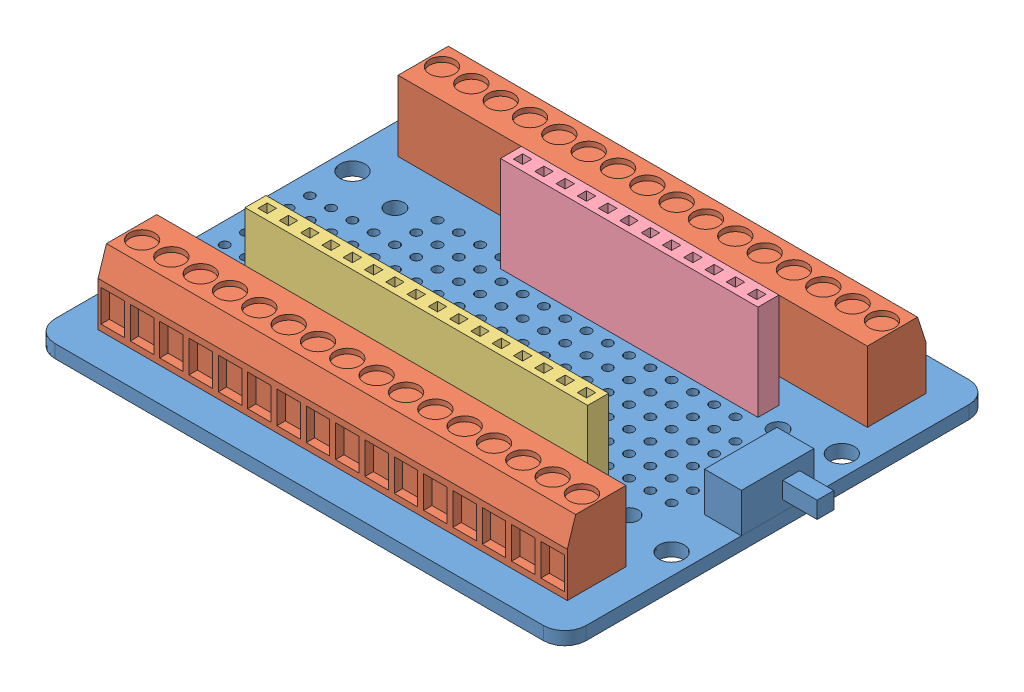
SolidWorks assembly 2926 Terminal Block Breakout FeatherWing, configuration Default. Lengths in mm.
Overall size (67.5 15.2 50.8).
5 component instances, 4 part files, 9 mates.
Components (placement in the parent):
- 2926 Terminal Block Breakout FeatherWing-1: 2926 Terminal Block Breakout FeatherWing [Default] at origin size (67.5 6.27 50.8)
- screw_terminal_16x_3.5pitch-1: screw_terminal_16x_3.5pitch [Default] at (-28 1.57 14.4) x (0 0 1) z (-1 0 0) size (7 12.2 56)
- screw_terminal_16x_3.5pitch-2: screw_terminal_16x_3.5pitch [Default] at (28 1.57 -14.4) x (0 0 -1) z (1 0 0) size (7 12.2 56)
- header_f16_tall-1: header_f16_tall [Default] at (-20.445 1.57 10.16) size (40.89 14.4 2.5)
- header_f12_tall-1: header_f12_tall [Default] at (-10.285 1.57 -10.16) size (30.73 14.4 2.5)
Mates (geometry in assembly coordinates):
- Coincident1: coincident anti-aligned: plane of 2926 Terminal Block Breakout FeatherWing-1 through (0 1.57 0) normal (0 1 0); plane of screw_terminal_16x_3.5pitch-1 through (28 1.57 21.4) normal (0 -1 0)
- Distance1: distance = 11 mm anti-aligned: plane of screw_terminal_16x_3.5pitch-1 through (28 1.57 14.4) normal (0 0 -1); plane of 2926 Terminal Block Breakout FeatherWing-1 through (-31.7 1.57 25.4) normal (0 0 1)
- Coincident3: coincident anti-aligned: plane of screw_terminal_16x_3.5pitch-1 through (0 1.57 14.4) normal (-1 0 0)
- Concentric1: concentric aligned: cylinder of 2926 Terminal Block Breakout FeatherWing-1 through (-19.05 1.57 10.16) axis (0 -1 0) radius 0.55; line of header_f16_tall-1 through (-19.05 1.57 10.16) axis (0 -1 0)
- Concentric2: concentric aligned: cylinder of 2926 Terminal Block Breakout FeatherWing-1 through (19.05 1.57 10.16) axis (0 -1 0) radius 0.55; line of header_f16_tall-1 through (19.05 1.57 10.16) axis (0 -1 0)
- Coincident4: coincident anti-aligned: plane of 2926 Terminal Block Breakout FeatherWing-1 through (0 1.57 0) normal (0 1 0); plane of header_f16_tall-1 through (-20.445 1.57 11.41) normal (0 -1 0)
- Concentric3: concentric aligned: cylinder of 2926 Terminal Block Breakout FeatherWing-1 through (-8.89 1.57 -10.16) axis (0 -1 0) radius 0.55; line of header_f12_tall-1 through (-8.89 1.57 -10.16) axis (0 -1 0)
- Concentric4: concentric aligned: cylinder of 2926 Terminal Block Breakout FeatherWing-1 through (19.05 1.57 -10.16) axis (0 -1 0) radius 0.55; line of header_f12_tall-1 through (19.05 1.57 -10.16) axis (0 -1 0)
- Coincident5: coincident anti-aligned: plane of 2926 Terminal Block Breakout FeatherWing-1 through (0 1.57 0) normal (0 1 0); plane of header_f12_tall-1 through (-10.285 1.57 -8.91) normal (0 -1 0)
